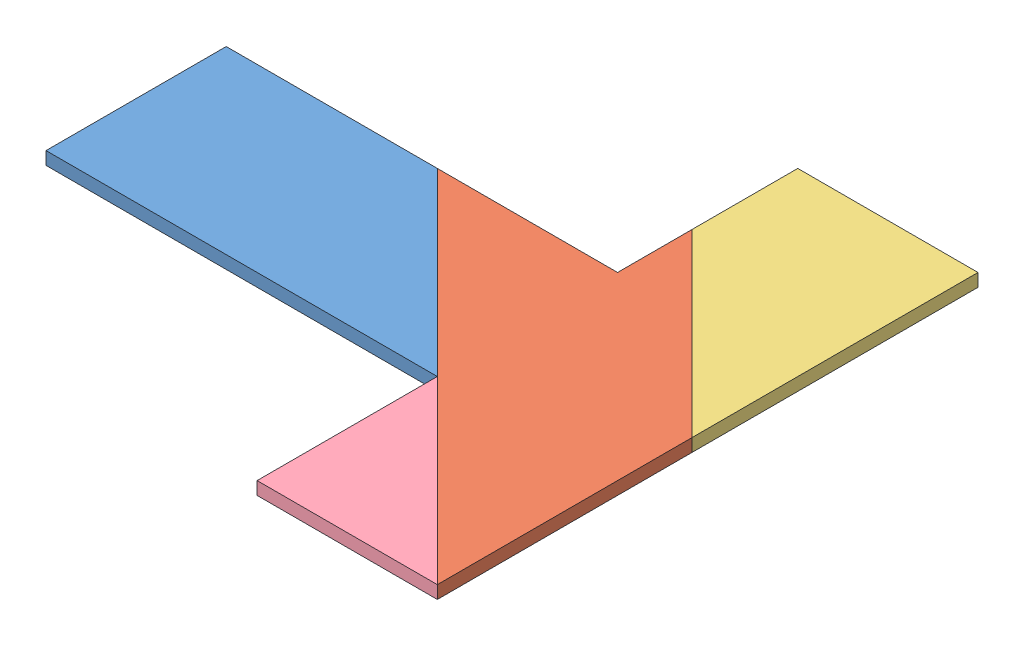
SolidWorks assembly Assem1, configuration Default. Lengths in mm.
Overall size (162.9 3 126).
4 component instances, 4 part files, 9 mates.
Components (placement in the parent):
- T_Puzzle_Part1-1: T_Puzzle_Part1 [Default] at origin size (91.2 3 42)
- T_Puzzle_Part2-1: T_Puzzle_Part2 [Default] at (57.0798 0 9.5202) x (-0.707107 0 -0.707107) z (0.707107 0 -0.707107) size (118.8 3 42)
- T_Puzzle_Part3-1: T_Puzzle_Part3 [Default] at (66.6 0 -29.6957) x (0 0 1) z (-1 0 0) size (66.6 3 42)
- T_Puzzle_Part4-1: T_Puzzle_Part4 [Default] at (66.6 3 51.2894) x (-1 0 0) z (0 0 1) size (42 3 42)
Mates (geometry in assembly coordinates):
- Coincident17: coincident aligned: plane of T_Puzzle_Part1-1 through (-45.6 3 -21) normal (0 0 -1); plane of T_Puzzle_Part2-1 through (3.5957 3 -21) normal (0 0 -1)
- Coincident20: coincident aligned: plane of T_Puzzle_Part1-1 through (0 3 0) normal (0 1 0); plane of T_Puzzle_Part2-1 through (57.0798 3 9.5202) normal (0 1 0)
- Coincident23: coincident aligned: line of T_Puzzle_Part1-1 through (3.5957 3 -21) axis (0 -1 0); line of T_Puzzle_Part2-1 through (3.5957 3 -21) axis (0 -1 0)
- Coincident24: coincident aligned: plane of T_Puzzle_Part2-1 through (57.0798 3 9.5202) normal (0 1 0); plane of T_Puzzle_Part4-1 through (66.6 3 51.2894) normal (0 1 0)
- Coincident25: coincident anti-aligned: line of T_Puzzle_Part2-1 through (87.6 3 63.0043) axis (0 -1 0); line of T_Puzzle_Part4-1 through (87.6 0 63.0043) axis (0 1 0)
- Coincident27: coincident anti-aligned: plane of T_Puzzle_Part2-1 through (87.6 3 63.0043) normal (-0.707107 0 0.707107); plane of T_Puzzle_Part4-1 through (87.6 0 63.0043) normal (0.707107 0 -0.707107)
- Coincident28: coincident: plane of T_Puzzle_Part2-1 through (87.6 3 3.6043) normal (0.707107 0 -0.707107); plane of T_Puzzle_Part3-1 through (87.6 -58.4195 3.6043) normal (-0.707107 0 0.707107)
- Coincident30: coincident: line of T_Puzzle_Part2-1 through (87.6 3 3.6043) axis (0 -1 0); line of T_Puzzle_Part3-1 through (87.6 3 3.6043) axis (0 -1 0)
- Coincident31: coincident aligned: plane of T_Puzzle_Part2-1 through (57.0798 3 9.5202) normal (0 1 0); plane of T_Puzzle_Part3-1 through (66.6 3 -29.6957) normal (0 1 0)
